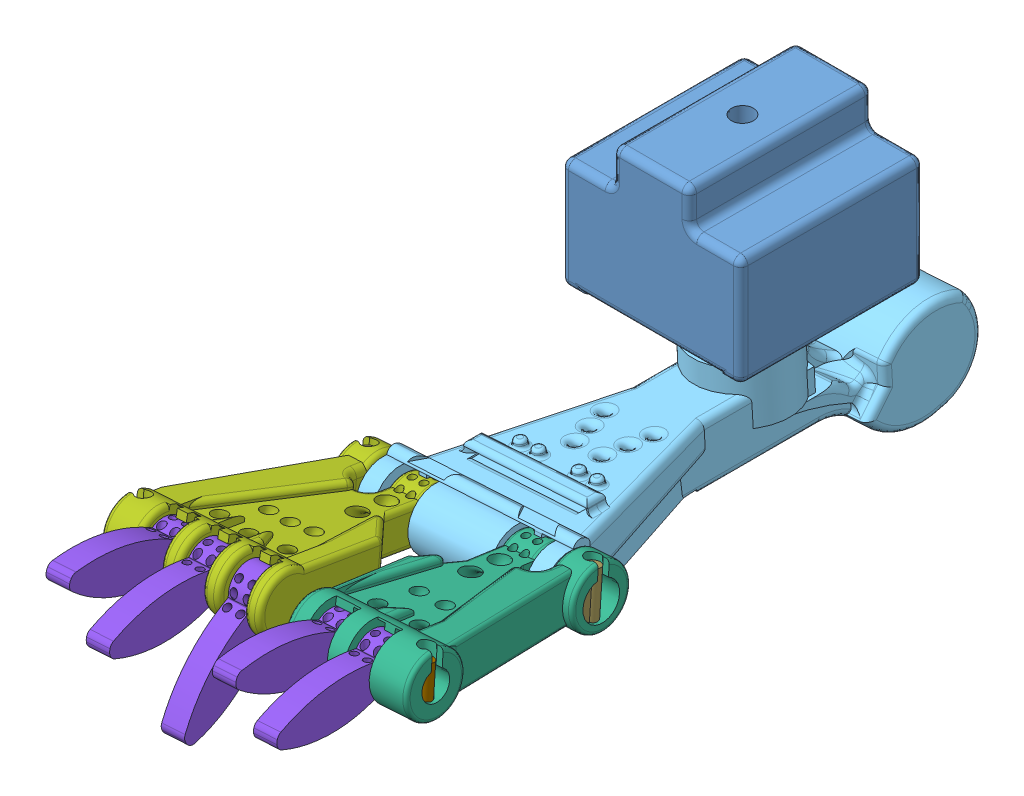
SolidWorks assembly Foot Ankle, configuration Default. Lengths in mm.
Overall size (108.56 105.58 260.86).
22 component instances, 15 part files, 53 mates.
Components (placement in the parent):
- Ankle Exterior-1: Ankle Exterior [Default] at (-20.5538 13.3388 22.6611) size (62.23 50.8 63.5)
- Ankle Middle Joint Shell-1: Ankle Middle Joint Shell [Default] at (30.5162 13.8468 51.8711) x (-1 0 0) z (0 0 1) size (40.89 25.02 50.04)
- Ankle Interior Joint-1: Ankle Interior Joint [Default] at (30.7702 13.8468 51.8711) x (-1 0 0) z (0 0 1) size (45.97 24.51 48.01)
- Ankle Bottom Joint-1: Ankle Bottom Joint [Default] at (10.3232 11.3068 37.5281) x (0.998145 0.060874 0) z (0 0 1) size (27.55 36.83 34.71)
- New foot - Copy - Copy-1: New foot - Copy - Copy [Default] at (24.9461 11.4547 16.707) x (0 0 1) z (-0.998145 -0.060874 0) size (165.6 39.34 64.86)
- Left mid foot-1: Left mid foot [Default] at (43.9471 6.3016 206.9636) x (-0.998145 -0.060874 0) z (0.008077 -0.132437 -0.991159) size (43.26 21.17 83.82)
- New Front foot-1: New Front foot [Default] at (-21.0825 -1.088 207.2318) x (0.998145 0.060874 0) z (0.009651 -0.158247 -0.987352) size (55.48 21.27 83.82)
- Toe-1: Toe [Default] at (-3.9679 -6.3256 208.2385) x (0.998145 0.060874 0) z (0.041094 -0.673814 0.737757) size (8.13 14.73 49.22)
- Toe-2: Toe [Default] at (24.8614 -6.2124 208.4802) x (0.998145 0.060874 0) z (-0.012272 0.20123 0.979467) size (8.13 14.73 49.22)
- Toe-3: Toe [Default] at (-18.9261 -7.2378 208.2385) x (0.998145 0.060874 0) z (0.004596 -0.075365 0.997145) size (8.13 14.73 49.22)
- Toe-4: Toe [Default] at (-33.3772 -8.1192 208.2385) x (0.998145 0.060874 0) z (-0.015136 0.248186 0.968594) size (8.13 14.73 49.22)
- Toe-5: Toe [Default] at (39.3126 -5.331 208.4802) x (0.998145 0.060874 0) z (0.004596 -0.075365 0.997145) size (8.13 14.73 49.22)
- small axle lock-1: small axle lock [Default] at (-41.362 -14.8875 209.2452) x (-0.009651 0.158247 0.987352) z (-0.998145 -0.060874 0) size (6.6 12.7 4.83)
- small axle-1: small axle [Default] at (7.1874 -5.6452 208.2385) x (-0.056576 0.927664 0.369105) z (0.022469 -0.36842 0.929388) size (7.14 45.47 8.76)
- foot axle-1: foot axle [Default] at (6.0255 -15.8021 145.5416) x (0.04183 -0.685888 -0.726504) z (-0.044225 0.725156 -0.687163) size (12.32 29.21 12.32)
- large axle lock-1: large axle lock [Default] at (-25.7478 -26.5338 146.951) x (0.998145 0.060874 0) z (-0.009651 0.158247 0.987352) size (5.08 17.78 8.76)
- small axle - Copy-2: small axle - Copy [Default] at (50.7214 -4.6352 208.4802) x (-0.060224 0.987482 0.145783) z (0.008874 -0.145512 0.989317) size (7.14 30.48 8.76)
- foot axle-2: foot axle [Default] at (19.0361 -15.0086 145.5416) x (-0.025636 0.420358 -0.906996) z (0.055213 -0.905314 -0.421139) size (12.32 29.21 12.32)
- large axle lock-2: large axle lock [Default] at (52.0439 -22.148 146.6256) x (0.966152 0.024481 -0.256808) z (0.250817 0.143686 0.957311) size (5.08 17.78 8.76)
- small axle lock-2: small axle lock [Default] at (57.4746 -11.0524 209.3927) x (0.470396 0.145421 0.870391) z (-0.88039 0.009897 0.474146) size (6.6 12.7 4.83)
- Ankle Lock 1-1: Ankle Lock 1 [Default] at (9.6964 11.3068 50.4741) x (0 0 1) z (-1 0 0) size (22.86 14.73 2.03)
- Foot T Lock-1: Foot T Lock [Default] at (12.0769 -8.1806 49.2121) x (1 0 0) z (0 1 0) size (4 12.7 4)
Mates (geometry in assembly coordinates):
- Concentric1: concentric aligned: circle of Ankle Middle Joint Shell-1; circle of Ankle Interior Joint-1
- Coincident1: coincident aligned: plane of Ankle Middle Joint Shell-1 through (30.5162 13.8468 51.8711) normal (1 0 0); plane of Ankle Interior Joint-1 through (30.5162 13.8468 51.8711) normal (1 0 0)
- Coincident2: coincident anti-aligned: plane of Ankle Middle Joint Shell-1 through (30.5162 13.8468 51.8711) normal (0 -1 0); plane of Ankle Interior Joint-1 through (30.7702 13.8468 51.8711) normal (0 1 0)
- Distance1: distance = 1 mm anti-aligned: plane of Ankle Interior Joint-1 through (30.5162 13.8468 51.8711) normal (1 0 0); plane of Ankle Exterior-1 through (31.5162 16.3868 26.4711) normal (-1 0 0)
- LimitAngle1: limit planar angle = 0.349066 rad aligned: plane of Ankle Middle Joint Shell-1 through (30.5162 13.8468 51.8711) normal (0 -1 0); plane of Ankle Exterior-1 through (-20.5538 23.8372 24.4227) normal (0 -0.939693 -0.34202)
- Concentric4: concentric aligned: circle of Ankle Exterior-1; circle of Ankle Middle Joint Shell-1
- Concentric5: concentric anti-aligned: circle of Ankle Interior Joint-1; circle of Ankle Bottom Joint-1
- Distance2: distance = 0.5 mm anti-aligned: plane of Ankle Bottom Joint-1 through (10.3232 11.3068 67.8811) normal (0 0 1); plane of Ankle Interior Joint-1 through (-3.0118 11.3068 68.3811) normal (0 0 -1)
- LimitAngle2: limit planar angle = 0 rad anti-aligned: plane of Ankle Interior Joint-1 through (30.7702 11.3068 51.8711) normal (0 -1 0); plane of Ankle Bottom Joint-1 through (-2.6167 3.0107 37.5281) normal (-0.540433 0.841387 0)
- Coincident6: coincident: plane of Ankle Bottom Joint-1 through (23.9431 12.1374 48.3866) normal (0 0 -1); line of New foot - Copy - Copy-1 through (22.5834 0.476 48.3866) axis (-0.998145 -0.060874 0)
- Parallel1: parallel anti-aligned: plane of Ankle Bottom Joint-1 through (10.9958 0.2783 37.5281) normal (0.060874 -0.998145 0); plane of New foot - Copy - Copy-1 through (11.6603 -0.1902 53.4666) normal (-0.060874 0.998145 0)
- Concentric9: concentric aligned: circle of New Front foot-1; circle of Toe-1
- Coincident10: coincident anti-aligned: plane of New Front foot-1 through (3.7634 0.4273 207.2318) normal (-0.998145 -0.060874 0); plane of Toe-1 through (4.145 -5.8308 208.2385) normal (0.998145 0.060874 0)
- Concentric10: concentric aligned: circle of New Front foot-1; circle of Toe-3
- Coincident11: coincident anti-aligned: circle of New Front foot-1; plane of Toe-3 through (-18.9261 -7.2378 208.2385) normal (-0.998145 -0.060874 0)
- Concentric11: concentric aligned: circle of New Front foot-1; circle of Toe-4
- Coincident12: coincident anti-aligned: circle of New Front foot-1; plane of Toe-4 through (-33.3772 -8.1192 208.2385) normal (-0.998145 -0.060874 0)
- Concentric12: concentric aligned: circle of Left mid foot-1; circle of Toe-2
- Coincident13: coincident aligned: circle of Left mid foot-1; plane of Toe-2 through (24.8614 -6.2124 208.4802) normal (-0.998145 -0.060874 0)
- Concentric13: concentric aligned: circle of Left mid foot-1; circle of Toe-5
- Coincident14: coincident anti-aligned: circle of Left mid foot-1; plane of Toe-5 through (39.3126 -5.331 208.4802) normal (-0.998145 -0.060874 0)
- Concentric14: concentric anti-aligned: cylinder of New Front foot-1 through (-39.8632 -18.6008 145.5416) axis (0.998145 0.060874 0) radius 6.35; circle of foot axle-1
- Concentric15: concentric anti-aligned: circle of New Front foot-1; cylinder of small axle-1 through (-38.1943 -8.4129 208.2385) axis (0.998145 0.060874 0) radius 4.3815
- Concentric16: concentric aligned: circle of Left mid foot-1; circle of small axle-2
- Concentric18: concentric aligned: circle of Left mid foot-1; circle of foot axle-2
- Coincident20: coincident: plane of New Front foot-1 through (7.1874 -5.6452 208.2385) normal (-0.998145 -0.060874 0); line of small axle-1 through (6.9283 -1.3975 207.1956) axis (0.022469 -0.36842 0.929388)
- Concentric20: concentric anti-aligned: cylinder of New Front foot-1 through (-41.9727 -4.8746 207.6344) axis (-0.060104 0.985521 -0.158541) radius 2.54; cylinder of small axle lock-1 through (-42.1254 -2.3713 207.2318) axis (0.060104 -0.985521 0.158541) radius 2.413
- Concentric21: concentric aligned: cylinder of New Front foot-1 through (23.3474 -4.6597 208.2385) axis (-0.998145 -0.060874 0) radius 4.826; cylinder of small axle lock-1 through (-40.476 -8.5521 208.2385) axis (-0.998145 -0.060874 0) radius 4.191
- Concentric24: concentric aligned: circle of New Front foot-1; circle of large axle lock-1
- Coincident23: coincident: line of New Front foot-1 through (-28.4867 -11.5931 146.3196) axis (-0.060104 0.985521 -0.158541); cylinder of large axle lock-1 through (-26.8165 -9.0112 144.1322) axis (0.060104 -0.985521 0.158541) radius 2.54
- Concentric25: concentric anti-aligned: circle of New foot - Copy - Copy-1; cylinder of foot axle-2 through (48.1919 -13.2305 145.5416) axis (-0.998145 -0.060874 0) radius 6.1595
- Concentric26: concentric anti-aligned: circle of New foot - Copy - Copy-1; cylinder of foot axle-1 through (-23.1303 -17.5803 145.5416) axis (0.998145 0.060874 0) radius 6.1595
- Coincident24: coincident aligned: plane of New foot - Copy - Copy-1 through (19.0361 -15.0086 145.5416) normal (0.998145 0.060874 0); circle of foot axle-2
- Coincident25: coincident aligned: plane of New foot - Copy - Copy-1 through (4.4395 10.2041 16.707) normal (-0.998145 -0.060874 0); circle of foot axle-1
- Concentric28: concentric anti-aligned: circle of Left mid foot-1; cylinder of foot axle-2 through (48.1919 -13.2305 145.5416) axis (-0.998145 -0.060874 0) radius 6.1595
- Coincident26: coincident anti-aligned: circle of New foot - Copy - Copy-1; plane of Left mid foot-1 through (26.5122 -12.4173 209.3227) normal (-0.998145 -0.060874 0)
- Concentric29: concentric aligned: circle of New Front foot-1; cylinder of foot axle-1 through (-23.1303 -17.5803 145.5416) axis (0.998145 0.060874 0) radius 6.1595
- Coincident27: coincident anti-aligned: plane of New foot - Copy - Copy-1 through (-3.1664 9.7402 16.707) normal (-0.998145 -0.060874 0); plane of New Front foot-1 through (-1.8115 -12.4754 209.2452) normal (0.998145 0.060874 0)
- Concentric31: concentric anti-aligned: circle of Ankle Bottom Joint-1; cylinder of New foot - Copy - Copy-1 through (12.0769 -8.1806 28.0666) axis (0 0 1) radius 2.032
- Coincident30: coincident anti-aligned: plane of Left mid foot-1 through (20.2979 -6.4907 208.4802) normal (0.998145 0.060874 0); circle of small axle - Copy-2
- Parallel3: parallel aligned: plane of Ankle Exterior-1 through (-20.5538 13.3388 83.6211) normal (0 0 1); plane of Ankle Interior Joint-1 through (30.7702 13.8468 78.9221) normal (0 0 1)
- Parallel6: parallel aligned: plane of Ankle Interior Joint-1 through (30.7702 11.3068 51.8711) normal (0 -1 0); plane of Ankle Bottom Joint-1 through (10.3232 0.2578 37.5281) normal (0 -1 0)
- Concentric32: concentric anti-aligned: cylinder of Left mid foot-1 through (53.895 -52.4999 150.6962) axis (-0.060336 0.98932 -0.132683) radius 2.54; cylinder of large axle lock-2 through (50.9712 -4.5579 144.2665) axis (0.060336 -0.98932 0.132683) radius 2.54
- Coincident31: coincident: cylinder of Left mid foot-1 through (64.9248 -12.21 145.5416) axis (-0.998145 -0.060874 0) radius 6.35; point of large axle lock-2
- Concentric33: concentric anti-aligned: cylinder of Left mid foot-1 through (59.4657 -43.7008 213.7713) axis (-0.060336 0.98932 -0.132683) radius 2.54; cylinder of small axle lock-2 through (56.7083 1.512 207.7076) axis (0.060336 -0.98932 0.132683) radius 2.413
- Coincident33: coincident: cylinder of Left mid foot-1 through (5.6591 -7.3835 208.4802) axis (0.998145 0.060874 0) radius 4.826; point of small axle lock-2
- Lock1: lock: unknown of Left mid foot-1; unknown of large axle lock-2
- Lock2: lock: unknown of Left mid foot-1; unknown of small axle lock-2
- Concentric34: concentric aligned: circle of Ankle Interior Joint-1; cylinder of Ankle Lock 1-1 through (24.4202 26.0388 51.9981) axis (0 -1 0) radius 1.016
- Parallel8: parallel anti-aligned: plane of Ankle Interior Joint-1 through (25.6902 24.0068 64.4441) normal (-1 0 0); plane of Ankle Lock 1-1 through (25.4362 24.0068 40.5681) normal (1 0 0)
- Coincident34: coincident: plane of Ankle Interior Joint-1 through (30.7702 24.0068 51.8711) normal (0 -1 0); line of Ankle Lock 1-1 through (23.4042 24.0068 40.5681) axis (0 0 1)
- Concentric35: concentric anti-aligned: cylinder of New foot - Copy - Copy-1 through (12.0769 -8.1806 28.0666) axis (0 0 1) radius 2.032; circle of Foot T Lock-1
- Coincident35: coincident anti-aligned: plane of Ankle Bottom Joint-1 through (12.0769 -8.1806 49.2121) normal (0 0 -1); plane of Foot T Lock-1 through (12.0769 -8.1806 49.2121) normal (0 0 1)
